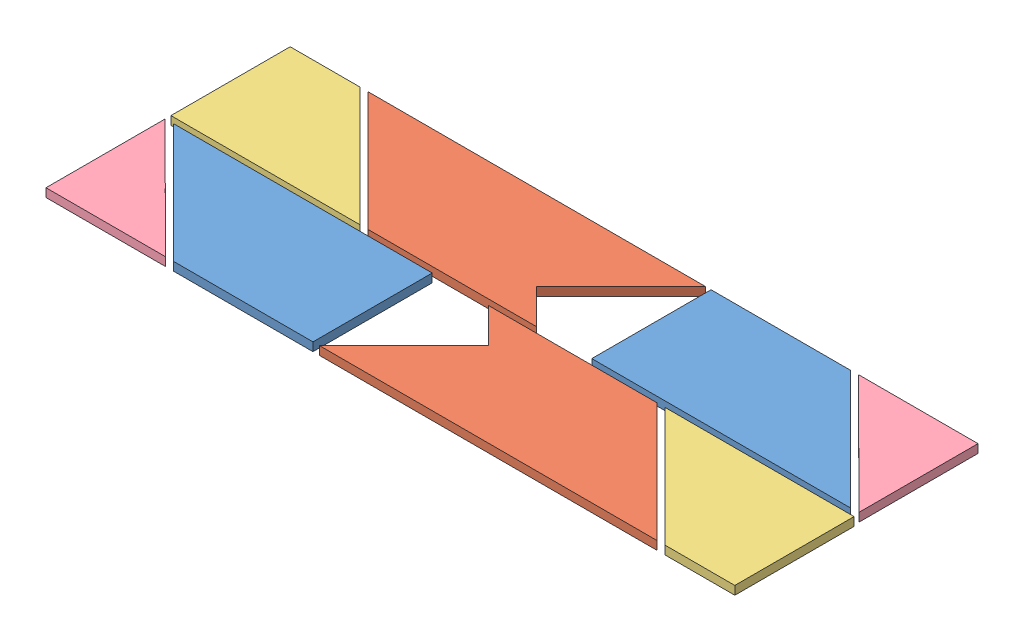
SolidWorks assembly T_Puzzle_Assem1 - Copy, configuration Default. Lengths in mm.
Overall size (242.61 3 86.07).
8 component instances, 4 part files, 21 mates.
Components (placement in the parent):
- T_Puzzle_Part1-1: T_Puzzle_Part1 [Default] at origin size (91.2 3 42)
- T_Puzzle_Part2-1: T_Puzzle_Part2 [Default] at (-38.0445 0 48.7643) x (-1 0 0) z (0 0 -1) size (118.8 3 42)
- T_Puzzle_Part3-1: T_Puzzle_Part3 [Default] at (15.4818 3 44) x (-1 0 0) z (0 0 1) size (66.6 3 42)
- T_Puzzle_Part4-1: T_Puzzle_Part4 [Default] at (27.3551 3 -9.356) x (1 0 -0.000051) z (-0.000051 0 -1) size (42 3 42)
- T_Puzzle_Part4-2: T_Puzzle_Part4 [Default] at (-182.1102 0 43.9994) x (0.000051 0 1) z (-1 0 0.000051) size (42 3 42)
- T_Puzzle_Part2-2: T_Puzzle_Part2 [Default] at (-107 0 -4.7643) size (118.8 3 42)
- T_Puzzle_Part1-2: T_Puzzle_Part1 [Default] at (-145.3976 0 44) x (-1 0 0) z (0 0 -1) size (91.2 3 42)
- T_Puzzle_Part3-2: T_Puzzle_Part3 [Default] at (-160.5263 3 0) x (1 0 0) z (0 0 -1) size (66.6 3 42)
Mates (geometry in assembly coordinates):
- Distance1: distance = 2 mm anti-aligned: plane of T_Puzzle_Part4-1 through (6.3545 0 -21.0698) normal (-0.707071 0 0.707143); plane of T_Puzzle_Part1-1 through (45.6 3 21) normal (0.707071 0 -0.707143)
- Parallel2: parallel anti-aligned: line of T_Puzzle_Part1-1 through (3.5957 3 -21) axis (0 -1 0); line of T_Puzzle_Part4-1 through (6.3545 0 -21.0698) axis (0 1 0)
- Coincident4: coincident aligned: plane of T_Puzzle_Part1-1 through (0 3 0) normal (0 1 0); plane of T_Puzzle_Part4-1 through (27.3551 3 -9.356) normal (0 1 0)
- Coincident5: coincident aligned: plane of T_Puzzle_Part1-1 through (0 3 0) normal (0 1 0); plane of T_Puzzle_Part3-1 through (15.4818 3 44) normal (0 1 0)
- Coincident6: coincident aligned: plane of T_Puzzle_Part1-1 through (0 3 0) normal (0 1 0); plane of T_Puzzle_Part2-1 through (-38.0445 3 48.7643) normal (0 1 0)
- Distance3: distance = 2 mm anti-aligned: plane of T_Puzzle_Part2-1 through (-20.6467 3 23) normal (0 0 -1); plane of T_Puzzle_Part1-1 through (-45.6 3 21) normal (0 0 1)
- Distance4: distance = 2 mm anti-aligned: plane of T_Puzzle_Part3-1 through (48.7818 0 23) normal (0 0 -1); plane of T_Puzzle_Part1-1 through (-45.6 3 21) normal (0 0 1)
- Distance5: distance = 2 mm anti-aligned: plane of T_Puzzle_Part3-1 through (-17.8182 0 23) normal (-0.707107 0 0.707107); plane of T_Puzzle_Part2-1 through (21.3555 3 65.0021) normal (0.707107 0 -0.707107)
- Distance6: distance = 2 mm anti-aligned: plane of T_Puzzle_Part1-2 through (-190.9976 3 23) normal (-0.707071 0 0.707143); plane of T_Puzzle_Part4-2 through (-193.8262 3 23) normal (0.707071 0 -0.707143)
- Parallel5: parallel aligned: plane of T_Puzzle_Part2-1 through (21.3555 3 65.0021) normal (0 0 1); plane of T_Puzzle_Part1-2 through (-124.3976 3 65) normal (0 0 1)
- Coincident15: coincident aligned: plane of T_Puzzle_Part1-1 through (0 3 0) normal (0 1 0); plane of T_Puzzle_Part1-2 through (-169.9976 3 44) normal (0 1 0)
- Coincident16: coincident aligned: plane of T_Puzzle_Part2-1 through (-38.0445 3 48.7643) normal (0 1 0); plane of T_Puzzle_Part2-2 through (-107 3 -4.7643) normal (0 1 0)
- Coincident18: coincident aligned: plane of T_Puzzle_Part4-2 through (-206.7102 3 43.9994) normal (0 1 0); plane of T_Puzzle_Part1-2 through (-169.9976 3 44) normal (0 1 0)
- Distance7: distance = 2 mm anti-aligned: plane of T_Puzzle_Part2-2 through (-124.3979 3 21) normal (0 0 1); plane of T_Puzzle_Part2-1 through (-20.6467 3 23) normal (0 0 -1)
- Distance9: distance = 2 mm anti-aligned: plane of T_Puzzle_Part1-2 through (-99.7976 3 23) normal (0 0 -1); plane of T_Puzzle_Part2-2 through (-124.3979 3 21) normal (0 0 1)
- Coincident33: coincident: line of T_Puzzle_Part4-2 through (-218.4262 3 23) axis (0 -1 0); plane of T_Puzzle_Part1-2 through (-124.3976 3 23) normal (0 0 -1)
- Distance12: distance = 2 mm: plane of T_Puzzle_Part1-1 through (-45.6 3 -21) normal (-1 0 0); line of T_Puzzle_Part2-2 through (-47.6 3 -21.0021) axis (0 -1 0)
- Distance13: distance = 2 mm anti-aligned: plane of T_Puzzle_Part3-2 through (-127.2263 0 21) normal (0.707107 0 -0.707107); plane of T_Puzzle_Part2-2 through (-166.4 3 -21.0021) normal (-0.707107 0 0.707107)
- Coincident35: coincident aligned: plane of T_Puzzle_Part2-2 through (-107 3 -4.7643) normal (0 1 0); plane of T_Puzzle_Part3-2 through (-160.5263 3 0) normal (0 1 0)
- Coincident36: coincident: plane of T_Puzzle_Part2-2 through (-124.3979 3 21) normal (0 0 1); line of T_Puzzle_Part3-2 through (-127.2263 0 21) axis (0 1 0)
- Coincident37: coincident: plane of T_Puzzle_Part4-2 through (-193.8262 3 23) normal (-1 0 0.000051); line of T_Puzzle_Part3-2 through (-193.8263 0 21) axis (0 1 0)
